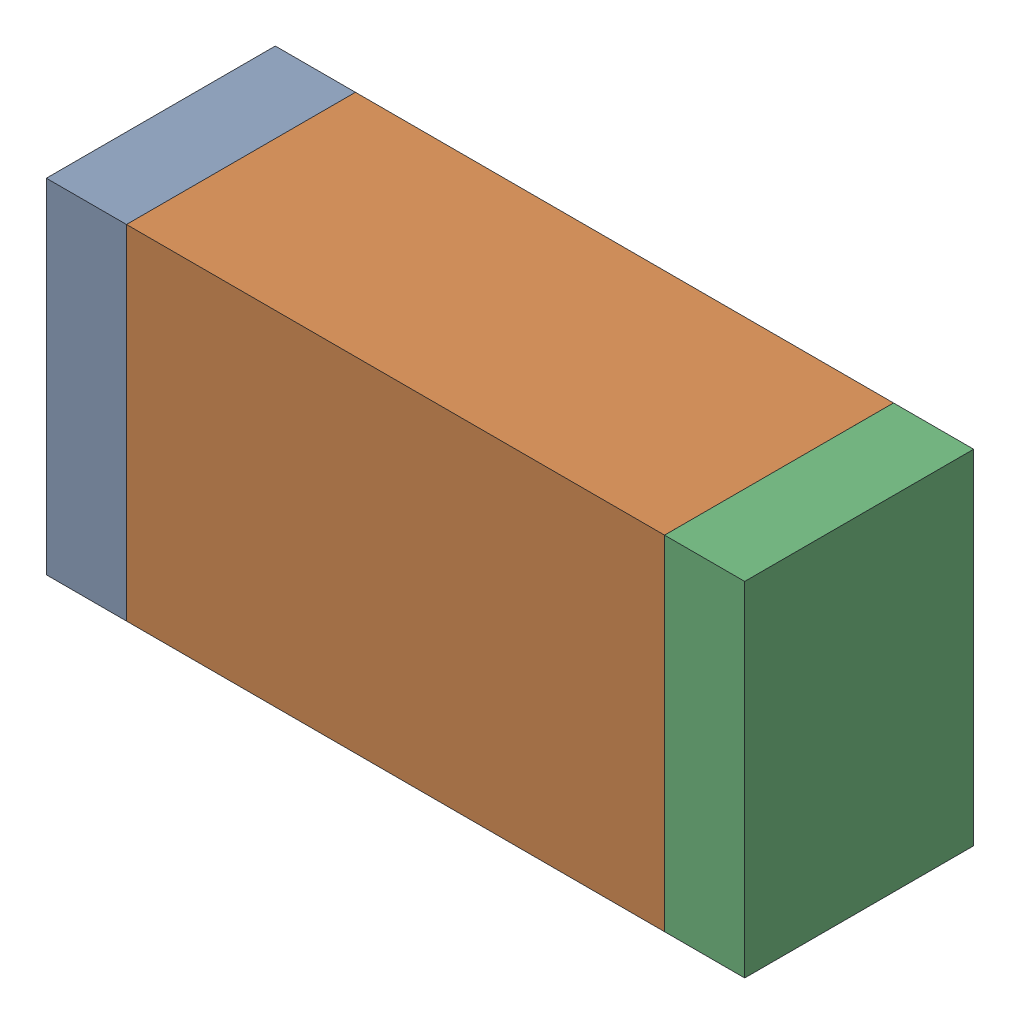
SolidWorks assembly R10, configuration Default. Lengths in mm.
Overall size (1.55 0.76 0.51).
6 component instances, 2 part files, 0 mates.
Components (placement in the parent):
- 822490216-1: 822490216 [Default] at (46.6089 19.5833 0) size (0.18 0.76 0.51)
  - Extruded-1: Extruded [Default] at origin size (0.18 0.76 0.51)
- 822498920-1: 822498920 [Default] at (47.2947 19.5833 0) size (1.19 0.76 0.51)
  - Extruded_2-1: Extruded_2 [Default] at origin size (1.19 0.76 0.51)
- 822490216-2: 822490216 [Default] at (47.9805 19.5833 0) size (0.18 0.76 0.51)
  - Extruded-1: Extruded [Default] at origin size (0.18 0.76 0.51)
